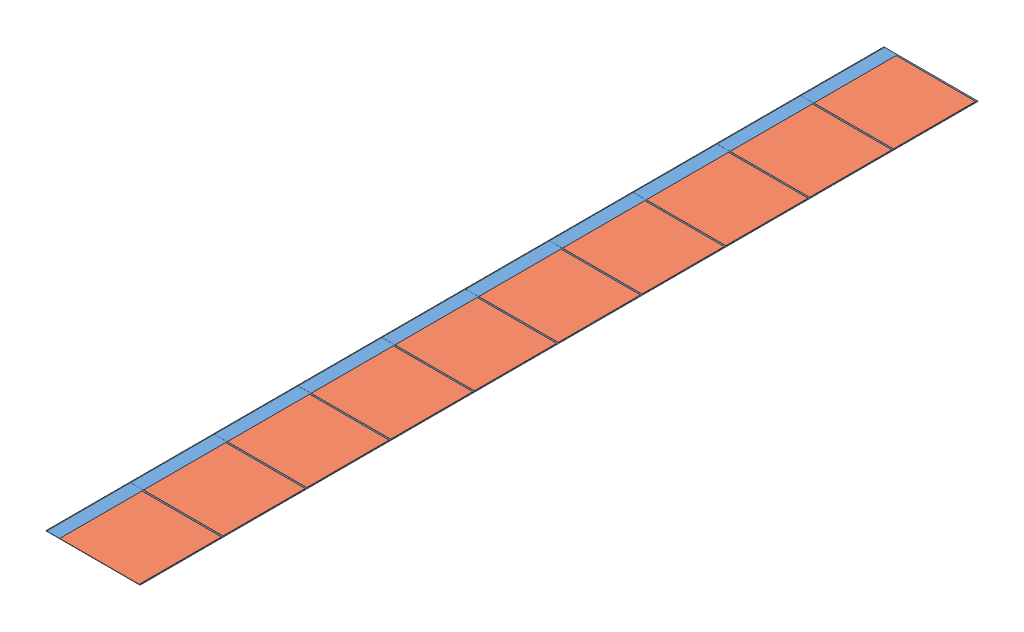
SolidWorks assembly chip array u, configuration Default. Lengths in mm.
Overall size (22.73 0.05 202.49).
40 component instances, 3 part files, 3 mates.
Components (placement in the parent):
- chip u-11: chip u [Default] at (0 0 91.2906) size (22.73 0.05 20.24)
  - chip u frame-1: chip u frame [Default] at origin size (22.73 0.05 20.24)
  - chip u active-1: chip u active [Default] at (1.533 0 0.1554) size (19.21 0.05 19.87)
  - chip u pads-2: chip u pads [Default] at (-11.2796 0 -0.0043) size (0.13 0.05 20.19)
- chip u-12: chip u [Default] at (0 0 71.0406) size (22.73 0.05 20.24)
  - chip u frame-1: chip u frame [Default] at origin size (22.73 0.05 20.24)
  - chip u active-1: chip u active [Default] at (1.533 0 0.1554) size (19.21 0.05 19.87)
  - chip u pads-2: chip u pads [Default] at (-11.2796 0 -0.0043) size (0.13 0.05 20.19)
- chip u-13: chip u [Default] at (0 0 50.7906) size (22.73 0.05 20.24)
  - chip u frame-1: chip u frame [Default] at origin size (22.73 0.05 20.24)
  - chip u active-1: chip u active [Default] at (1.533 0 0.1554) size (19.21 0.05 19.87)
  - chip u pads-2: chip u pads [Default] at (-11.2796 0 -0.0043) size (0.13 0.05 20.19)
- chip u-14: chip u [Default] at (0 0 30.5406) size (22.73 0.05 20.24)
  - chip u frame-1: chip u frame [Default] at origin size (22.73 0.05 20.24)
  - chip u active-1: chip u active [Default] at (1.533 0 0.1554) size (19.21 0.05 19.87)
  - chip u pads-2: chip u pads [Default] at (-11.2796 0 -0.0043) size (0.13 0.05 20.19)
- chip u-15: chip u [Default] at (0 0 10.2906) size (22.73 0.05 20.24)
  - chip u frame-1: chip u frame [Default] at origin size (22.73 0.05 20.24)
  - chip u active-1: chip u active [Default] at (1.533 0 0.1554) size (19.21 0.05 19.87)
  - chip u pads-2: chip u pads [Default] at (-11.2796 0 -0.0043) size (0.13 0.05 20.19)
- chip u-16: chip u [Default] at (0 0 -9.9594) size (22.73 0.05 20.24)
  - chip u frame-1: chip u frame [Default] at origin size (22.73 0.05 20.24)
  - chip u active-1: chip u active [Default] at (1.533 0 0.1554) size (19.21 0.05 19.87)
  - chip u pads-2: chip u pads [Default] at (-11.2796 0 -0.0043) size (0.13 0.05 20.19)
- chip u-17: chip u [Default] at (0 0 -30.2094) size (22.73 0.05 20.24)
  - chip u frame-1: chip u frame [Default] at origin size (22.73 0.05 20.24)
  - chip u active-1: chip u active [Default] at (1.533 0 0.1554) size (19.21 0.05 19.87)
  - chip u pads-2: chip u pads [Default] at (-11.2796 0 -0.0043) size (0.13 0.05 20.19)
- chip u-18: chip u [Default] at (0 0 -50.4594) size (22.73 0.05 20.24)
  - chip u frame-1: chip u frame [Default] at origin size (22.73 0.05 20.24)
  - chip u active-1: chip u active [Default] at (1.533 0 0.1554) size (19.21 0.05 19.87)
  - chip u pads-2: chip u pads [Default] at (-11.2796 0 -0.0043) size (0.13 0.05 20.19)
- chip u-19: chip u [Default] at (0 0 -70.7094) size (22.73 0.05 20.24)
  - chip u frame-1: chip u frame [Default] at origin size (22.73 0.05 20.24)
  - chip u active-1: chip u active [Default] at (1.533 0 0.1554) size (19.21 0.05 19.87)
  - chip u pads-2: chip u pads [Default] at (-11.2796 0 -0.0043) size (0.13 0.05 20.19)
- chip u-20: chip u [Default] at (0 0 -90.9594) size (22.73 0.05 20.24)
  - chip u frame-1: chip u frame [Default] at origin size (22.73 0.05 20.24)
  - chip u active-1: chip u active [Default] at (1.533 0 0.1554) size (19.21 0.05 19.87)
  - chip u pads-2: chip u pads [Default] at (-11.2796 0 -0.0043) size (0.13 0.05 20.19)
Mates (geometry in assembly coordinates):
- Coincident1: coincident aligned: plane of chip u-11 through (0 0 90.9696) normal (0 1 0); plane of assembly through (0 0 0) normal (0 1 0)
- Coincident2: coincident aligned: plane of chip u-11 through (0 0 90.9696) normal (1 0 0); plane of assembly through (0 0 0) normal (1 0 0)
- Distance1: distance = 0.132 mm: line of chip u-16/chip u active-1 through (-8.0718 0.05 0.132) axis (1 0 0); plane of assembly
